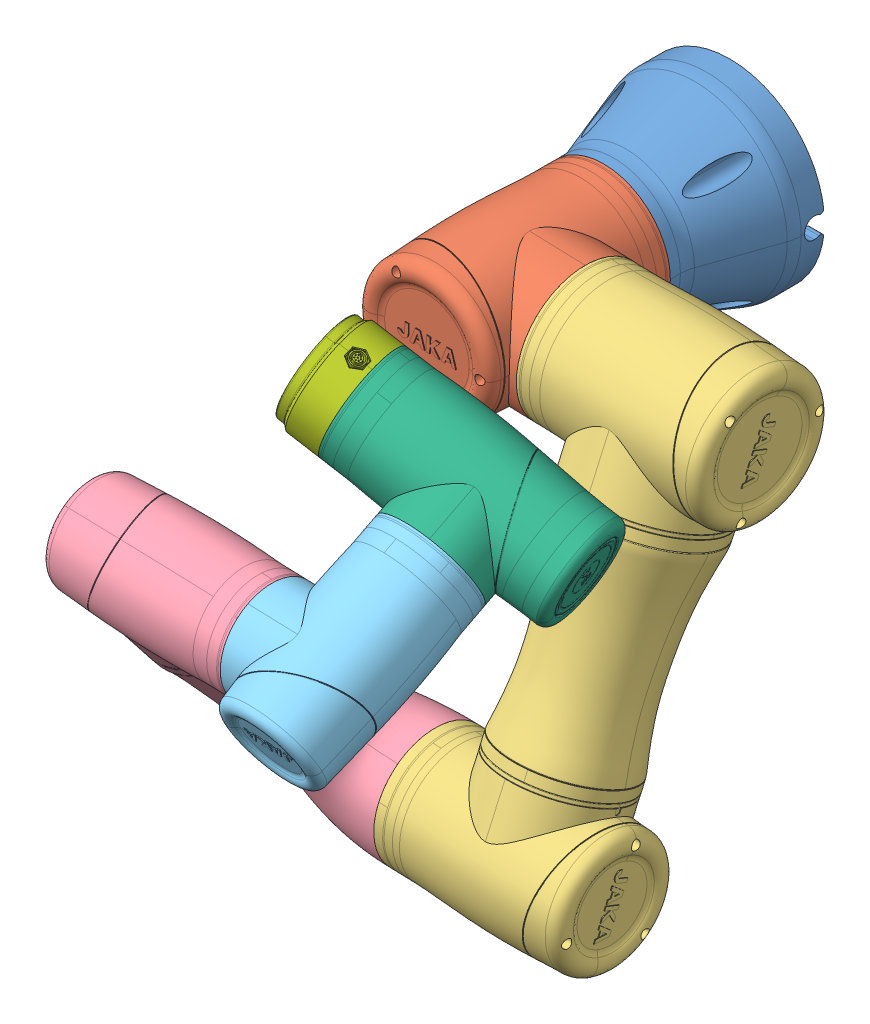
SolidWorks assembly JAKA Zu 3 211210, configuration Default. Lengths in mm.
Overall size (251.38 375.45 442.44).
7 component instances, 7 part files, 9 mates.
Components (placement in the parent):
- Copy of Zu 3 00_____^JAKA Zu 3 211210-1: Copy of Zu 3 00_____^JAKA Zu 3 211210 [Default] x (1 0 0) z (0 -1 0) size (129 86.05 129) (virtual)
- Copy of Zu 3 01_____^JAKA Zu 3 211210-1: Copy of Zu 3 01_____^JAKA Zu 3 211210 [Default] at (0 0 86.05) x (0.99946 -0.032854 0) z (-0.032854 -0.99946 0) size (100.15 123.51 99.3) (virtual)
- Copy of Zu 3 02_____^JAKA Zu 3 211210-1: Copy of Zu 3 02_____^JAKA Zu 3 211210 [Default] at (50.4727 -1.6591 150.55) x (-0.030513 -0.928257 0.370686) z (0.012178 0.370486 0.928758) size (340.28 129.01 99.3) (virtual)
- Copy of Zu 3 03_____^JAKA Zu 3 211210-1: Copy of Zu 3 03_____^JAKA Zu 3 211210 [Default] at (-10.5046 -228.2526 241.7389) x (0.025755 0.783498 0.62086) z (-0.99946 0.032854 0) size (304.09 81.52 124.06) (virtual)
- Copy of Zu 3 04_____^JAKA Zu 3 211210-1: Copy of Zu 3 04_____^JAKA Zu 3 211210 [Default] at (112.4945 -17.2358 316.4754) x (-0.99946 0.032854 0) z (0.028885 0.87873 0.476445) size (76.84 124.06 70.89) (virtual)
- Copy of Zu 3 05_____^JAKA Zu 3 211210-1: Copy of Zu 3 05_____^JAKA Zu 3 211210 [Default] at (43.9654 30.3622 294.6862) x (-0.015653 -0.476188 0.879204) z (0.414113 0.797264 0.439181) size (76.84 140.28 70.89) (virtual)
- Copy of Zu 3 06_____^JAKA Zu 3 211210-1: Copy of Zu 3 06_____^JAKA Zu 3 211210 [Default] at (17.5845 41.4773 299.3836) x (0.406642 0.885306 0.225556) z (-0.079857 0.28039 -0.956559) size (68.5 29 68) (virtual)
Mates (geometry in assembly coordinates):
- Coincident1: coincident anti-aligned: plane of Copy of Zu 3 01_____^JAKA Zu 3 211210-1 through (50.4727 -1.6591 150.55) normal (0.99946 -0.032854 0); plane of Copy of Zu 3 02_____^JAKA Zu 3 211210-1 through (50.4727 -1.6591 150.55) normal (-0.99946 0.032854 0)
- Coincident2: coincident anti-aligned: circle of Copy of Zu 3 01_____^JAKA Zu 3 211210-1; circle of Copy of Zu 3 02_____^JAKA Zu 3 211210-1
- Coincident3: coincident aligned: circle of Copy of Zu 3 00_____^JAKA Zu 3 211210-1; circle of Copy of Zu 3 01_____^JAKA Zu 3 211210-1
- Coincident4: coincident anti-aligned: plane of Copy of Zu 3 02_____^JAKA Zu 3 211210-1 through (37.4694 -229.8296 241.7389) normal (-0.99946 0.032854 0); plane of Copy of Zu 3 03_____^JAKA Zu 3 211210-1 through (37.4694 -229.8296 241.7389) normal (0.99946 -0.032854 0)
- Coincident5: coincident: point of Copy of Zu 3 02_____^JAKA Zu 3 211210-1; cylinder of Copy of Zu 3 03_____^JAKA Zu 3 211210-1 through (37.4694 -229.8296 241.7389) axis (0.99946 -0.032854 0) radius 39.5
- Coincident6: coincident: point of Copy of Zu 3 02_____^JAKA Zu 3 211210-1; cylinder of Copy of Zu 3 03_____^JAKA Zu 3 211210-1 through (37.4694 -229.8296 241.7389) axis (0.99946 -0.032854 0) radius 39.5
- Coincident7: coincident anti-aligned: circle of Copy of Zu 3 03_____^JAKA Zu 3 211210-1; circle of Copy of Zu 3 04_____^JAKA Zu 3 211210-1
- Coincident8: coincident anti-aligned: circle of Copy of Zu 3 04_____^JAKA Zu 3 211210-1; circle of Copy of Zu 3 05_____^JAKA Zu 3 211210-1
- Coincident9: coincident aligned: circle of Copy of Zu 3 05_____^JAKA Zu 3 211210-1; circle of Copy of Zu 3 06_____^JAKA Zu 3 211210-1
